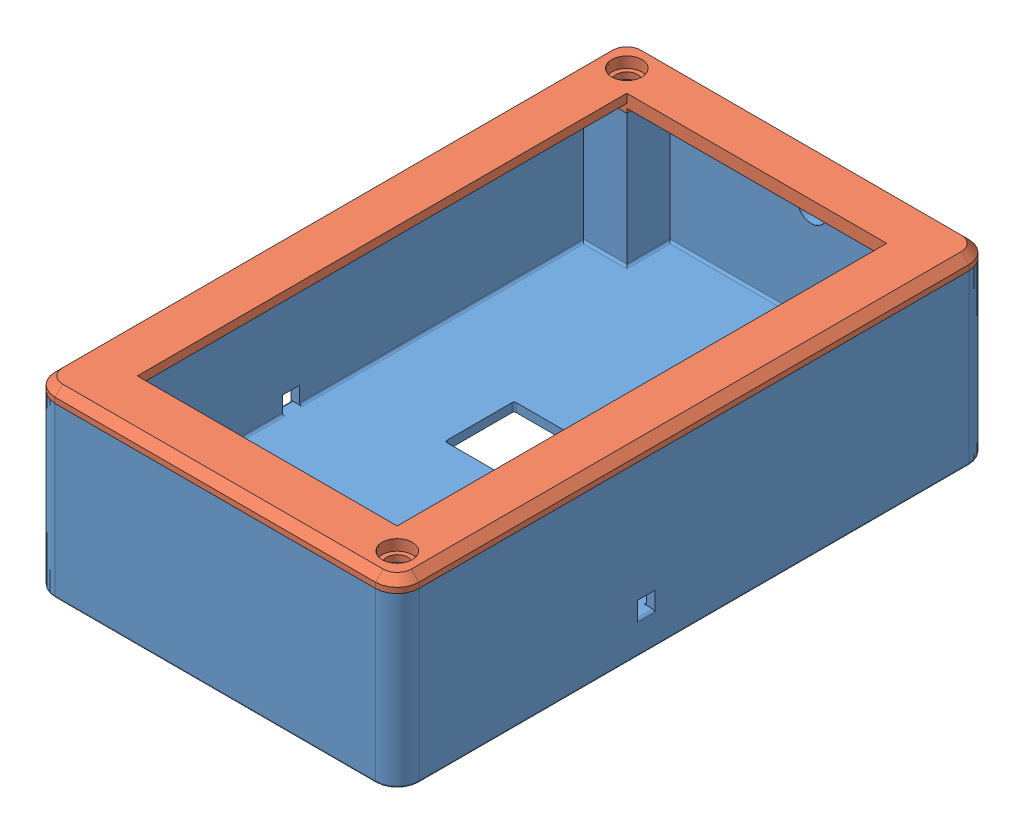
SolidWorks assembly Assem1, configuration Default. Lengths in mm.
Overall size (84 41.94 137).
4 component instances, 4 part files, 9 mates.
Components (placement in the parent):
- addonBack-2: addonBack [Default] at (1.1852 108.1055 106.7178) size (84 38.94 137)
- addonBackCover-2: addonBackCover [Default] at (85.1852 152.7055 106.7178) x (-1 0 0) z (0 0 1) size (84 4 137)
- board-1: board [Default] at (3.1852 128.1054 104.7178) size (76 1.6 129) (hidden)
- glass-1: glass [Default] at (3.4352 148.7055 94.7178) size (79.5 2 113) (hidden)
Mates (geometry in assembly coordinates):
- Coincident4: coincident anti-aligned: plane of addonBack-2 through (1.1852 148.7055 106.7178) normal (0 1 0); plane of addonBackCover-2 through (6.1852 148.7055 -25.2822) normal (0 -1 0)
- Coincident5: coincident aligned: plane of addonBack-2 through (1.1852 149.7055 -30.2822) normal (0 0 -1); plane of addonBackCover-2 through (85.1852 149.7055 -30.2822) normal (0 0 -1)
- Coincident6: coincident aligned: plane of addonBack-2 through (1.1852 149.7055 106.7178) normal (-1 0 0); plane of addonBackCover-2 through (1.1852 149.7055 106.7178) normal (-1 0 0)
- Coincident8: coincident anti-aligned: plane of addonBack-2 through (1.1852 128.1054 106.7178) normal (0 1 0); plane of board-1 through (3.1852 128.1054 104.7178) normal (0 -1 0)
- Distance1: distance = 2 mm anti-aligned: plane of board-1 through (11.1852 129.7054 102.7178) normal (0 0 1); plane of addonBack-2 through (80.1852 118.1054 104.7178) normal (0 0 -1)
- Distance2: distance = 2 mm anti-aligned: plane of board-1 through (81.1852 129.7054 92.7178) normal (1 0 0); plane of addonBack-2 through (83.1852 118.1054 -25.2822) normal (-1 0 0)
- Coincident11: coincident anti-aligned: plane of addonBackCover-2 through (3.4352 148.7055 -18.2822) normal (0 0 1); plane of glass-1 through (3.4352 150.7055 -18.2822) normal (0 0 -1)
- Coincident12: coincident anti-aligned: plane of addonBackCover-2 through (3.4352 150.7055 94.7178) normal (1 0 0); plane of glass-1 through (3.4352 150.7055 94.7178) normal (-1 0 0)
- Coincident13: coincident anti-aligned: plane of addonBackCover-2 through (85.1852 150.7055 106.7178) normal (0 -1 0); plane of glass-1 through (3.4352 150.7055 94.7178) normal (0 1 0)
